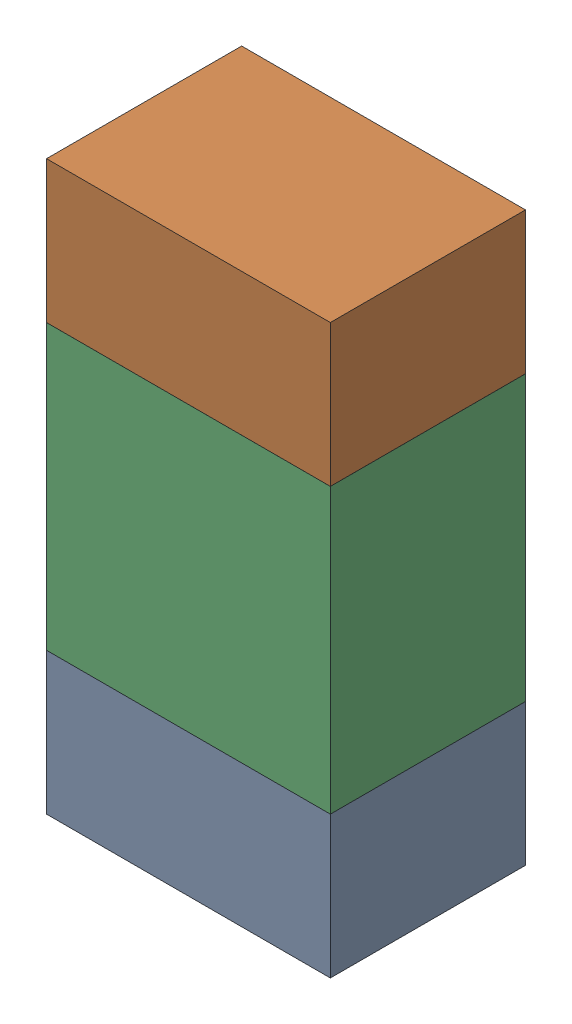
SolidWorks assembly R74, configuration ﾃﾞﾌｫﾙﾄ. Lengths in mm.
Overall size (0.8 1.6 0.55).
6 component instances, 2 part files, 0 mates.
Components (placement in the parent):
- 689261784-1: 689261784 [ﾃﾞﾌｫﾙﾄ] at (41.7499 68.4001 0) size (0.8 0.4 0.55)
  - Extruded_34-1: Extruded_34 [ﾃﾞﾌｫﾙﾄ] at origin size (0.8 0.4 0.55)
- 689261784-2: 689261784 [ﾃﾞﾌｫﾙﾄ] at (41.7499 69.6001 0) size (0.8 0.4 0.55)
  - Extruded_34-1: Extruded_34 [ﾃﾞﾌｫﾙﾄ] at origin size (0.8 0.4 0.55)
- 689261648-1: 689261648 [ﾃﾞﾌｫﾙﾄ] at (41.7499 69 0) size (0.8 0.8 0.55)
  - Extruded_33-1: Extruded_33 [ﾃﾞﾌｫﾙﾄ] at origin size (0.8 0.8 0.55)
